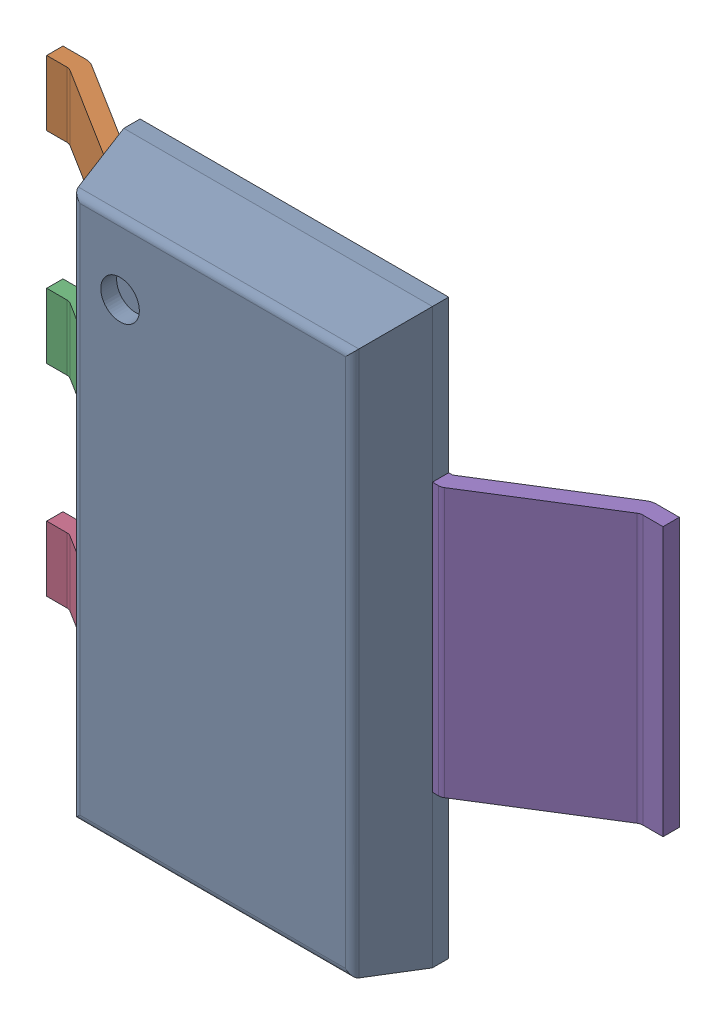
SolidWorks assembly IC1_2.step, configuration Default. Lengths in mm.
Overall size (7 6.51 1.8).
4 component instances, 3 part files, 0 mates.
Components (placement in the parent):
- 9655846400.step-1: 9655846400.step [Default] at (95.25 75.946 0) x (1 0 0) z (0 0 1) size (7 6.51 1.8)
  - Body_4.step-8: Body_4.step [Default] at origin size (3.5 6.51 1.06)
  - PinsArrayL_2.step-8: PinsArrayL_2.step [Default] at origin size (1.75 5.32 1.06)
  - FilletPinR_2.step-8: FilletPinR_2.step [Default] at origin size (1.75 3.05 1.06)
